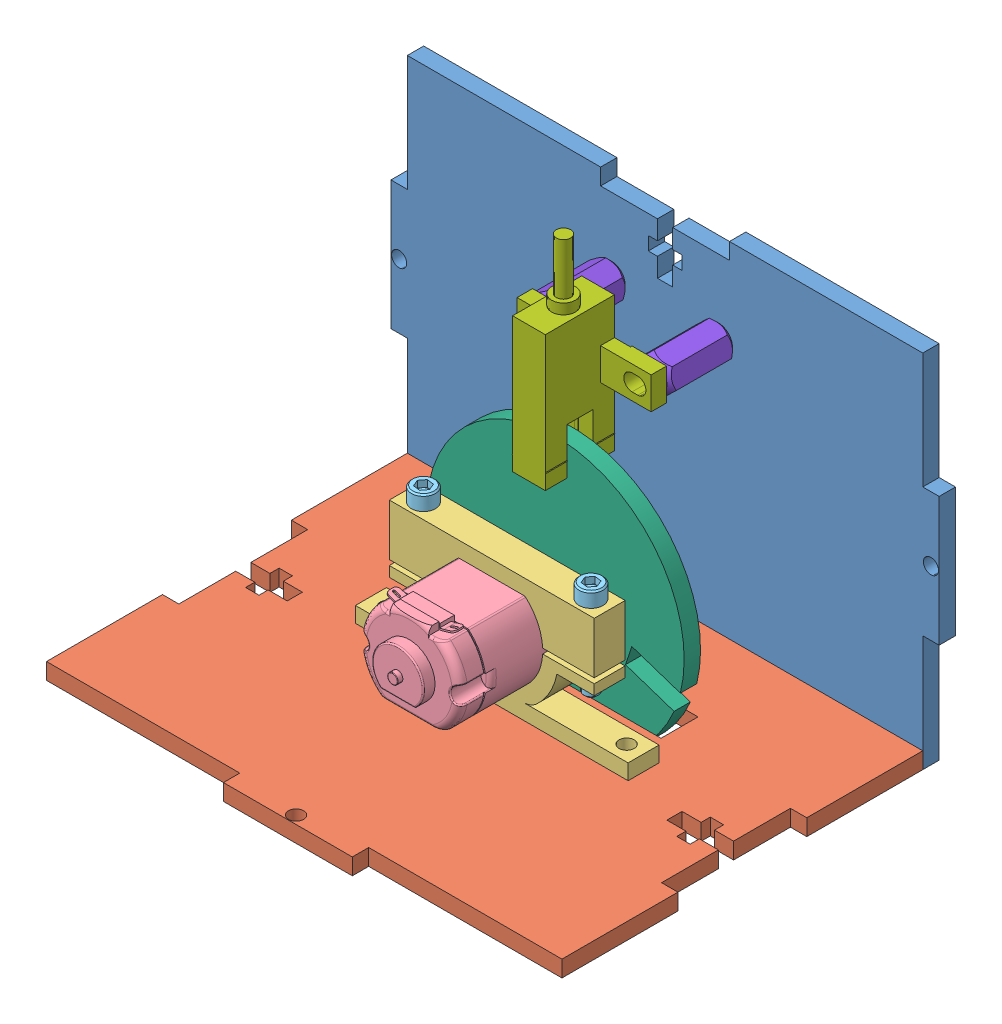
SolidWorks assembly PhotinterrupterMotorSubassem, configuration Default. Lengths in mm.
Overall size (106.35 89.8 76.35).
11 component instances, 8 part files, 15 mates.
Components (placement in the parent):
- PhotinterrupterMotorSubassemWall1-1: PhotinterrupterMotorSubassemWall1 [Default] at (35.9834 39.6411 54.7935) size (106.35 70 3.17)
- PhotinterrupterMotorSubassemWall2-1: PhotinterrupterMotorSubassemWall2 [Default] at (35.9834 6.2286 91.381) x (0 0 -1) z (0 1 0) size (76.35 100 3.17)
- MotorAssem-1: MotorAssem [Default] at (-3.0078 -15.4605 140.9197) x (0 1 0) z (0 0 -1) size (63.22 63.17 37.75)
  - MotorMount-1: MotorMount [Default] at (15.7766 38.9912 50.9262) size (24 52.9 6)
  - DCmotor-Size130-1: DCmotor-Size130 [Default] at (36.7766 38.9912 34.9262) size (16.47 19.75 37.75)
  - socket head cap screw_ai-11: socket head cap screw_ai [HX-SHCS 0.112-40x0.625x0.625-N] at (50.1214 55.2437 53.9262) x (-1 0 0) z (0 0.924225 0.381849) size (18.72 4.65 4.65)
  - socket head cap screw_ai-12: socket head cap screw_ai [HX-SHCS 0.112-40x0.625x0.625-N] at (50.1214 22.7387 53.9262) x (-1 0 0) z (0 0.924225 0.381849) size (18.72 4.65 4.65)
  - InterruptWheel-1: InterruptWheel [Default] at (36.7766 38.9912 64.8387) x (0.948715 0.316133 0) z (0 0 1) size (50 49.92 3.17)
- EE-SX672WR-1: EE-SX672WR [Default] at (45.4834 57.2161 69.081) x (0 0 -1) z (-1 0 0) size (13.7 38.4 26)
- 25x.5 Aluminum Hex Female Female Standoff-1: 25x.5 Aluminum Hex Female Female Standoff [Default] at (25.5834 57.2161 62.731) x (0.999498 0.031674 0) z (0 0 1) size (6.35 8.06 12.7)
- 25x.5 Aluminum Hex Female Female Standoff-2: 25x.5 Aluminum Hex Female Female Standoff [Default] at (46.3834 57.2161 62.731) x (0.973982 0.226625 0) z (0 0 1) size (6.35 8.06 12.7)
Mates (geometry in assembly coordinates):
- Coincident1: coincident aligned: plane of Wall1-1 through (35.9834 39.6411 53.206) normal (0 0 -1); plane of Wall2-1 through (23.4834 7.8161 53.206) normal (0 0 -1)
- Parallel1: parallel aligned: plane of Wall1-1 through (35.9834 74.6411 56.381) normal (0 1 0); plane of Wall2-1 through (35.9834 7.8161 91.381) normal (0 1 0)
- Coincident3: coincident aligned: line of Wall1-1 through (48.4834 4.6411 56.381) axis (1 0 0); line of Wall2-1 through (48.4834 4.6411 56.381) axis (1 0 0)
- Coincident4: coincident: line of Wall1-1 through (23.4834 7.8161 56.381) axis (0 0 -1); plane of Wall2-1 through (23.4834 7.8161 53.206) normal (-1 0 0)
- Coincident5: coincident anti-aligned: plane of Wall2-1 through (35.9834 7.8161 91.381) normal (0 1 0); plane of MotorAssem-1/MotorMount-1 through (35.9834 7.8161 89.9935) normal (0 -1 0)
- Coincident6: coincident anti-aligned: plane of Wall2-1 through (35.9834 6.2286 91.381) normal (-1 0 0); plane of MotorAssem-1/DCmotor-Size130-1 through (35.9834 21.3161 105.9935) normal (1 0 0)
- Parallel2: parallel anti-aligned: plane of Wall2-1 through (35.9834 4.6411 91.381) normal (0 -1 0); plane of EE-SX672WR-1 through (32.8084 76.8032 73.581) normal (0 1 0)
- Coincident9: coincident anti-aligned: point of Wall1-1; moEndPointRef_w of EE-SX672WR-1
- Concentric1: concentric aligned: circle of 25x.5 Aluminum Hex Female Female Standoff-1; circle of EE-SX672WR-1
- Coincident10: coincident anti-aligned: plane of EE-SX672WR-1 through (45.4834 66.5032 69.081) normal (0 0 -1); plane of 25x.5 Aluminum Hex Female Female Standoff-1 through (25.5834 66.5032 69.081) normal (0 0 1)
- Coincident11: coincident anti-aligned: plane of Wall1-1 through (35.9834 39.6411 56.381) normal (0 0 1); plane of 25x.5 Aluminum Hex Female Female Standoff-1 through (25.5834 66.5032 56.381) normal (0 0 -1)
- Concentric2: concentric aligned: circle of EE-SX672WR-1; circle of 25x.5 Aluminum Hex Female Female Standoff-2
- Coincident12: coincident anti-aligned: plane of EE-SX672WR-1 through (45.4834 66.5032 69.081) normal (0 0 -1); plane of 25x.5 Aluminum Hex Female Female Standoff-2 through (46.3834 66.5032 69.081) normal (0 0 1)
- Coincident17: coincident: plane of MotorAssem-1/InterruptWheel-1 through (35.9834 21.3161 76.081) normal (0 0 -1); line of EE-SX672WR-1 through (39.1584 59.6032 76.081) axis (0 1 0)
- Distance1: distance = 4 mm anti-aligned: plane of EE-SX672WR-1 through (39.1584 50.3161 78.581) normal (0 -1 0); cylinder of MotorAssem-1/InterruptWheel-1 through (35.9834 21.3161 74.4935) axis (0 0 1) radius 25
